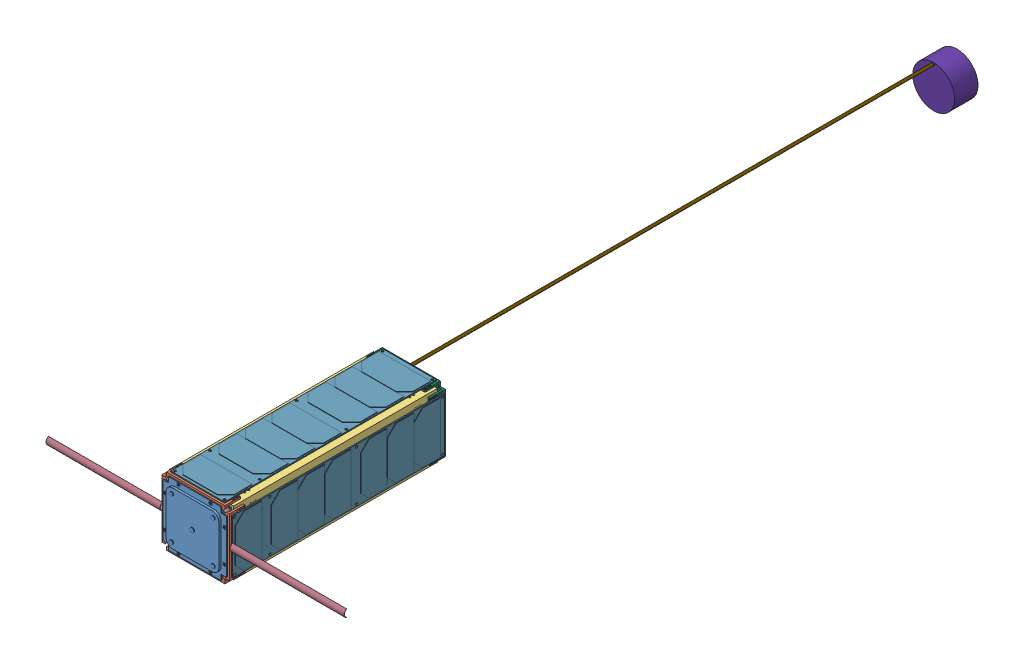
SolidWorks assembly RADIO Unstowed, configuration Default. Lengths in mm.
Overall size (457.2 117.23 1173).
77 component instances, 18 part files, 145 mates.
Components (placement in the parent):
- Nanocom Antenna-1: Nanocom Antenna [Default] at (54.7327 27.087 80.9297) size (98 98 11)
- Top Sipport-1: Top Sipport [Default] at (83.9034 50.4516 80.9297) x (0 -1 0) z (0 0 -1) size (89.4 11 24)
- Top Sipport-2: Top Sipport [Default] at (-15.8818 37.5538 80.9297) x (0 1 0) z (0 0 -1) size (89.4 11 24)
- Top Sipport-3: Top Sipport [Default] at (27.5619 93.8953 80.9297) x (1 0 0) z (0 0 -1) size (89.4 11 24)
- Top Sipport-4: Top Sipport [Default] at (40.4598 -5.8899 80.9297) x (-1 0 0) z (0 0 -1) size (89.4 11 24)
- Support-1: Support [Default] at (-14.9892 90.3455 -221.7132) x (0 -1 0) z (1 0 0) size (18 313 15)
- Support-2: Support [Default] at (-12.332 -4.9973 -221.7132) x (1 0 0) z (0 1 0) size (18 313 15)
- Support-3: Support [Default] at (80.3537 93.0027 -221.7132) x (-1 0 0) z (0 -1 0) size (18 313 15)
- Support-4: Support [Default] at (83.0108 -2.3402 -221.7132) x (0 1 0) z (-1 0 0) size (18 313 15)
- Top Plate2-1: Top Plate2 [Default] at (13.317 21.6849 56.9297) x (-1 0 0) z (0 0 -1) size (92 92 23)
- Nut-1: Nut [Default] at (-1.4892 79.5027 56.9297) size (11.55 10 5.32)
- Nut-2: Nut [Default] at (69.5108 8.5027 56.9297) x (0.821931 0.569587 0) z (0 0 1) size (11.55 10 5.32)
- Nut-3: Nut [Default] at (69.5108 79.5027 56.9297) size (11.55 10 5.32)
- Nut-4: Nut [Default] at (-1.4892 8.5027 56.9297) size (11.55 10 5.32)
- Threaded Rod2-1: Threaded Rod2 [Default] at (69.5108 8.5027 -231.0703) size (6.4 7.01 294.26)
- Threaded Rod2-2: Threaded Rod2 [Default] at (-1.4892 8.5027 -231.0703) size (6.4 7.01 294.26)
- Threaded Rod2-3: Threaded Rod2 [Default] at (-1.4892 79.5027 -231.0703) size (6.4 7.01 294.26)
- Threaded Rod2-4: Threaded Rod2 [Default] at (69.5108 79.5027 -231.0703) size (6.4 7.01 294.26)
- Mid Plate-1: Mid Plate [Default] at (4.649 54.0261 25.9297) size (86 86 3)
- Nut-5: Nut [Default] at (-1.4892 8.5027 20.9297) x (0.999286 -0.037791 0) z (0 0 1) size (11.55 10 5.32)
- Nut-6: Nut [Default] at (-1.4892 8.5027 28.9297) size (11.55 10 5.32)
- Nut-7: Nut [Default] at (69.5108 8.5027 28.9297) size (11.55 10 5.32)
- Nut-8: Nut [Default] at (69.5108 8.5027 20.9297) x (0.921379 0.388666 0) z (0 0 1) size (11.55 10 5.32)
- Nut-9: Nut [Default] at (69.5108 79.5027 28.9297) size (11.55 10 5.32)
- Nut-10: Nut [Default] at (-1.4892 79.5027 28.9297) size (11.55 10 5.32)
- Nut-11: Nut [Default] at (69.5108 79.5027 20.9297) x (0.963517 0.267648 0) z (0 0 1) size (11.55 10 5.32)
- Nut-12: Nut [Default] at (-1.4892 79.5027 20.9297) x (0.997929 0.06432 0) z (0 0 1) size (11.55 10 5.32)
- SDR-1: SDR [Default] at (37.1692 34.198 30.9297) size (65 40 16.8)
- TTC Radio-1: TTC Radio [Default] at (48.3672 78.5027 28.9297) x (0 1 0) z (0 0 1) size (19.7 16 5)
- Raspberry Pi-1: Raspberry Pi [Default] at (63.5108 49.6464 -55.0703) size (66 30.48 5)
- TTC Circuit-1: TTC Circuit [Default] at (24.4431 25.9578 10.9297) size (80 50 10)
- Battery-1: Battery [Default] at (21.7415 31.358 -37.0703) size (70.1 42.59 38.1)
- Tape Antenna-3: Tape Antenna [Default] at (-194.5892 44.2096 75.6458) x (0 -0.999378 0.035253) z (1 0 0) size (11.67 4.21 175)
- Tape Antenna-4: Tape Antenna [Default] at (262.6108 43.4652 75.6178) x (0 0.999544 0.030207) z (-1 0 0) size (11.67 4.21 175)
- Mid Plate-2: Mid Plate [Default] at (4.649 54.0261 7.9297) size (86 86 3)
- Nut-13: Nut [Default] at (-1.4892 8.5027 10.9297) size (11.55 10 5.32)
- Nut-14: Nut [Default] at (69.5108 79.5027 10.9297) size (11.55 10 5.32)
- Nut-15: Nut [Default] at (-1.4892 8.5027 2.9297) size (11.55 10 5.32)
- Nut-16: Nut [Default] at (-1.4892 79.5027 10.9297) size (11.55 10 5.32)
- Nut-17: Nut [Default] at (-1.4892 79.5027 2.9297) size (11.55 10 5.32)
- Nut-18: Nut [Default] at (69.5108 8.5027 2.9297) size (11.55 10 5.32)
- Nut-19: Nut [Default] at (69.5108 8.5027 10.9297) size (11.55 10 5.32)
- Nut-20: Nut [Default] at (69.5108 79.5027 2.9297) size (11.55 10 5.32)
- Mid Plate-3: Mid Plate [Default] at (4.649 54.0261 -40.0703) size (86 86 3)
- Nut-21: Nut [Default] at (69.5108 79.5027 -37.0703) size (11.55 10 5.32)
- Nut-22: Nut [Default] at (-1.4892 8.5027 -40.0703) x (-0.923728 -0.383049 0) z (0 0 -1) size (11.55 10 5.32)
- Nut-23: Nut [Default] at (-1.4892 79.5027 -40.0703) x (-0.923728 -0.383049 0) z (0 0 -1) size (11.55 10 5.32)
- Nut-24: Nut [Default] at (69.5108 8.5027 -37.0703) size (11.55 10 5.32)
- Nut-25: Nut [Default] at (69.5108 79.5027 -40.0703) x (-0.923728 -0.383049 0) z (0 0 -1) size (11.55 10 5.32)
- Nut-26: Nut [Default] at (69.5108 8.5027 -40.0703) x (-0.923728 -0.383049 0) z (0 0 -1) size (11.55 10 5.32)
- Nut-27: Nut [Default] at (-1.4892 8.5027 -37.0703) size (11.55 10 5.32)
- Nut-28: Nut [Default] at (-1.4892 79.5027 -37.0703) size (11.55 10 5.32)
- Nut-29: Nut [Default] at (-1.4892 8.5027 -63.0703) size (11.55 10 5.32)
- Nut-30: Nut [Default] at (69.5108 79.5027 -63.0703) size (11.55 10 5.32)
- Nut-31: Nut [Default] at (69.5108 8.5027 -63.0703) size (11.55 10 5.32)
- Nut-32: Nut [Default] at (-1.4892 8.5027 -55.0703) size (11.55 10 5.32)
- Nut-33: Nut [Default] at (-1.4892 79.5027 -55.0703) size (11.55 10 5.32)
- Nut-34: Nut [Default] at (69.5108 8.5027 -55.0703) size (11.55 10 5.32)
- Nut-35: Nut [Default] at (-1.4892 79.5027 -63.0703) size (11.55 10 5.32)
- Nut-36: Nut [Default] at (69.5108 79.5027 -55.0703) size (11.55 10 5.32)
- Mid Plate-4: Mid Plate [Default] at (4.649 54.0261 -58.0703) size (86 86 3)
- Top Plate2-2: Top Plate2 [Default] at (54.7047 21.6849 -226.0703) size (92 92 23)
- Nut-37: Nut [Default] at (69.5108 8.5027 -226.0703) x (-0.923728 -0.383049 0) z (0 0 -1) size (11.55 10 5.32)
- Nut-38: Nut [Default] at (69.5108 79.5027 -226.0703) x (-0.923728 -0.383049 0) z (0 0 -1) size (11.55 10 5.32)
- Nut-39: Nut [Default] at (-1.4892 8.5027 -226.0703) x (-0.923728 -0.383049 0) z (0 0 -1) size (11.55 10 5.32)
- Nut-40: Nut [Default] at (-1.4892 79.5027 -226.0703) x (-0.923728 -0.383049 0) z (0 0 -1) size (11.55 10 5.32)
- 3U Panel-1: 3U Panel [Default] at (-17.9892 -8.6653 1.9441) x (0 -1 0) z (-1 0 0) size (82.6 325 2.3)
- 3U Panel-5: 3U Panel [Default] at (86.6788 -7.9973 1.9441) x (1 0 0) z (0 -1 0) size (82.6 325 2.3)
- 3U Panel-6: 3U Panel [Default] at (86.0108 96.6707 1.9441) x (0 1 0) z (1 0 0) size (82.6 325 2.3)
- 3U Panel-7: 3U Panel [Default] at (-18.6571 96.0027 1.9441) x (-1 0 0) z (0 1 0) size (82.6 325 2.3)
- Top Support Solar Panel-1: Top Support Solar Panel [Default] at (27.5619 -3.8899 -250.0703) size (89.4 13 24)
- Top Support Solar Panel-2: Top Support Solar Panel [Default] at (81.9034 37.5538 -250.0703) x (0 1 0) z (0 0 1) size (89.4 13 24)
- Top Support Solar Panel-3: Top Support Solar Panel [Default] at (40.4598 91.8953 -250.0703) x (-1 0 0) z (0 0 1) size (89.4 13 24)
- Top Support Solar Panel-4: Top Support Solar Panel [Default] at (-13.8818 50.4516 -250.0703) x (0 -1 0) z (0 0 1) size (89.4 13 24)
- 1U Panel-1: 1U Panel [Default] at (10.1282 49.1305 -250.0703) x (-1 0 0) z (0 0 -1) size (98 98 2.3)
- Mass-1: Mass [Default] at (35.0433 65.173 -1086.0703) x (-0.924883 -0.380251 0) z (0 0 1) size (64 64 36)
- Deployed Boom-1: Deployed Boom [Default] at (35.2379 68.8164 -1050.0703) x (0 0 1) z (-0.999908 -0.013572 0) size (800 1.49 5.53)
Mates (geometry in assembly coordinates):
- Coincident1: coincident: circle of Nanocom Antenna-1; circle of Top Sipport-4
- Coincident2: coincident: circle of Nanocom Antenna-1; circle of Top Sipport-4
- Coincident3: coincident: circle of Nanocom Antenna-1; circle of Top Sipport-2
- Coincident4: coincident: circle of Nanocom Antenna-1; circle of Top Sipport-2
- Coincident5: coincident: circle of Nanocom Antenna-1; circle of Top Sipport-3
- Coincident6: coincident: circle of Nanocom Antenna-1; circle of Top Sipport-3
- Coincident7: coincident: circle of Nanocom Antenna-1; circle of Top Sipport-1
- Coincident8: coincident: circle of Nanocom Antenna-1; circle of Top Sipport-1
- Coincident9: coincident: circle of Top Sipport-2; circle of Support-1
- Coincident10: coincident: circle of Top Sipport-3; circle of Support-1
- Coincident11: coincident: circle of Top Sipport-3; circle of Support-3
- Coincident12: coincident: circle of Top Sipport-1; circle of Support-3
- Coincident13: coincident: circle of Top Sipport-2; circle of Support-2
- Coincident14: coincident: circle of Top Sipport-4; circle of Support-2
- Coincident16: coincident: circle of Top Sipport-4; circle of Support-4
- Coincident17: coincident: circle of Top Sipport-1; circle of Support-4
- Coincident20: coincident: circle of Support-1; circle of Top Plate2-1
- Coincident21: coincident: circle of Support-2; circle of Top Plate2-1
- Coincident22: coincident: circle of Top Plate2-1; circle of Nut-3
- Coincident23: coincident: circle of Top Plate2-1; circle of Nut-1
- Coincident24: coincident: circle of Top Plate2-1; circle of Nut-4
- Coincident25: coincident: circle of Top Plate2-1; circle of Nut-2
- Concentric1: concentric: circle of Top Plate2-1; circle of Threaded Rod2-1
- Coincident26: coincident: plane of Nut-2 through (69.5108 8.5027 61.9297) normal (0 0 1); plane of Threaded Rod2-1 through (69.5108 8.5027 61.9297) normal (0 0 1)
- Concentric2: concentric: circle of Top Plate2-1; circle of Threaded Rod2-4
- Coincident27: coincident: plane of Nut-3 through (69.5108 79.5027 61.9297) normal (0 0 1); plane of Threaded Rod2-4 through (69.5108 79.5027 61.9297) normal (0 0 1)
- Concentric3: concentric: circle of Top Plate2-1; circle of Threaded Rod2-2
- Coincident28: coincident: plane of Nut-4 through (-1.4892 8.5027 61.9297) normal (0 0 1); plane of Threaded Rod2-2 through (-1.4892 8.5027 61.9297) normal (0 0 1)
- Concentric4: concentric: circle of Top Plate2-1; circle of Threaded Rod2-3
- Coincident29: coincident: plane of Nut-1 through (-1.4892 79.5027 61.9297) normal (0 0 1); plane of Threaded Rod2-3 through (-1.4892 79.5027 61.9297) normal (0 0 1)
- Concentric5: concentric: circle of Threaded Rod2-4; circle of Mid Plate-1
- Concentric6: concentric: circle of Threaded Rod2-2; circle of Mid Plate-1
- Concentric7: concentric: circle of Threaded Rod2-2; circle of Nut-6
- Coincident30: coincident: plane of Mid Plate-1 through (4.649 54.0261 28.9297) normal (0 0 1); plane of Nut-6 through (-1.4892 8.5027 28.9297) normal (0 0 -1)
- Concentric8: concentric: circle of Threaded Rod2-2; circle of Nut-5
- Coincident31: coincident: plane of Mid Plate-1 through (4.649 54.0261 25.9297) normal (0 0 -1); plane of Nut-5 through (-1.4892 8.5027 25.9297) normal (0 0 1)
- Concentric9: concentric: circle of Threaded Rod2-1; circle of Nut-7
- Coincident32: coincident: plane of Mid Plate-1 through (4.649 54.0261 28.9297) normal (0 0 1); plane of Nut-7 through (69.5108 8.5027 28.9297) normal (0 0 -1)
- Concentric10: concentric: circle of Threaded Rod2-1; circle of Nut-8
- Coincident33: coincident: plane of Mid Plate-1 through (4.649 54.0261 25.9297) normal (0 0 -1); plane of Nut-8 through (69.5108 8.5027 25.9297) normal (0 0 1)
- Concentric11: concentric: circle of Threaded Rod2-4; circle of Nut-9
- Coincident34: coincident: plane of Mid Plate-1 through (4.649 54.0261 28.9297) normal (0 0 1); plane of Nut-9 through (69.5108 79.5027 28.9297) normal (0 0 -1)
- Concentric12: concentric: circle of Threaded Rod2-3; circle of Nut-10
- Coincident35: coincident: plane of Mid Plate-1 through (4.649 54.0261 28.9297) normal (0 0 1); plane of Nut-10 through (-1.4892 79.5027 28.9297) normal (0 0 -1)
- Concentric13: concentric: circle of Threaded Rod2-4; circle of Nut-11
- Coincident36: coincident: plane of Mid Plate-1 through (4.649 54.0261 25.9297) normal (0 0 -1); plane of Nut-11 through (69.5108 79.5027 25.9297) normal (0 0 1)
- Concentric14: concentric: circle of Threaded Rod2-3; circle of Nut-12
- Coincident37: coincident: plane of Mid Plate-1 through (4.649 54.0261 25.9297) normal (0 0 -1); plane of Nut-12 through (-1.4892 79.5027 25.9297) normal (0 0 1)
- Distance1: distance = 25 mm: plane of Mid Plate-1 through (4.649 54.0261 28.9297) normal (0 0 1); plane of Top Plate2-1 through (13.317 21.6849 53.9297) normal (0 0 -1)
- Coincident39: coincident: plane of Mid Plate-1 through (4.649 54.0261 28.9297) normal (0 0 1); plane of SDR-1 through (37.1692 34.198 28.9297) normal (0 0 -1)
- Distance4: distance = 12 mm: line of SDR-1 through (65.0108 16.0027 28.9297) axis (0 1 0); line of Mid Plate-1 through (77.0108 4.0027 28.9297) axis (0 1 0)
- Distance5: distance = 15 mm: line of SDR-1 through (0.0108 16.0027 28.9297) axis (1 0 0); line of Mid Plate-1 through (-5.9892 1.0027 28.9297) axis (1 0 0)
- Coincident46: coincident: plane of Mid Plate-1 through (4.649 54.0261 28.9297) normal (0 0 1); plane of TTC Radio-1 through (48.3672 78.5027 28.9297) normal (0 0 -1)
- Distance8: distance = 20 mm: plane of TTC Radio-1 through (57.0108 78.5027 30.9297) normal (1 0 0); plane of Mid Plate-1 through (77.0108 4.0027 28.9297) normal (1 0 0)
- Distance9: distance = 5 mm: plane of TTC Radio-1 through (48.3672 82.0027 30.9297) normal (0 1 0); line of Mid Plate-1 through (74.0108 87.0027 28.9297) axis (-1 0 0)
- Coincident53: coincident: plane of TTC Circuit-1 through (24.4431 25.9578 10.9297) normal (0 0 -1); plane of Mid Plate-2 through (4.649 54.0261 10.9297) normal (0 0 1)
- Distance10: distance = 5 mm: line of TTC Circuit-1 through (-4.4066 66.0027 12.9297) axis (0 -1 0); line of Mid Plate-2 through (-8.9892 84.0027 10.9297) axis (0 -1 0)
- Distance13: distance = 21.095 mm: line of TTC Circuit-1 through (75.5934 66.0027 12.9297) axis (-1 0 0); line of Mid Plate-2 through (74.0108 87.0027 10.9297) axis (-1 0 0)
- Concentric16: concentric: circle of Threaded Rod2-2; circle of Mid Plate-2
- Concentric18: concentric: circle of Threaded Rod2-4; circle of Mid Plate-2
- Concentric19: concentric: circle of Threaded Rod2-4; circle of Nut-14
- Coincident59: coincident: plane of Mid Plate-2 through (4.649 54.0261 10.9297) normal (0 0 1); plane of Nut-14 through (69.5108 79.5027 10.9297) normal (0 0 -1)
- Concentric20: concentric: circle of Threaded Rod2-4; circle of Nut-20
- Coincident60: coincident: plane of Mid Plate-2 through (4.649 54.0261 7.9297) normal (0 0 -1); plane of Nut-20 through (69.5108 79.5027 7.9297) normal (0 0 1)
- Concentric21: concentric: circle of Threaded Rod2-1; circle of Nut-19
- Coincident61: coincident: plane of Mid Plate-2 through (4.649 54.0261 10.9297) normal (0 0 1); plane of Nut-19 through (69.5108 8.5027 10.9297) normal (0 0 -1)
- Concentric22: concentric: circle of Threaded Rod2-1; circle of Nut-18
- Coincident62: coincident: plane of Mid Plate-2 through (4.649 54.0261 7.9297) normal (0 0 -1); plane of Nut-18 through (69.5108 8.5027 7.9297) normal (0 0 1)
- Concentric23: concentric: circle of Threaded Rod2-2; circle of Nut-13
- Coincident63: coincident: plane of Mid Plate-2 through (4.649 54.0261 10.9297) normal (0 0 1); plane of Nut-13 through (-1.4892 8.5027 10.9297) normal (0 0 -1)
- Concentric24: concentric: circle of Threaded Rod2-2; circle of Nut-15
- Coincident64: coincident: plane of Mid Plate-2 through (4.649 54.0261 7.9297) normal (0 0 -1); plane of Nut-15 through (-1.4892 8.5027 7.9297) normal (0 0 1)
- Concentric25: concentric: circle of Threaded Rod2-3; circle of Nut-16
- Coincident65: coincident: plane of Mid Plate-2 through (4.649 54.0261 10.9297) normal (0 0 1); plane of Nut-16 through (-1.4892 79.5027 10.9297) normal (0 0 -1)
- Concentric26: concentric: circle of Threaded Rod2-3; circle of Nut-17
- Coincident66: coincident: plane of Mid Plate-2 through (4.649 54.0261 7.9297) normal (0 0 -1); plane of Nut-17 through (-1.4892 79.5027 7.9297) normal (0 0 1)
- Distance14: distance = 15 mm: plane of Mid Plate-2 through (4.649 54.0261 10.9297) normal (0 0 1); plane of Mid Plate-1 through (4.649 54.0261 25.9297) normal (0 0 -1)
- Coincident68: coincident: circle of Mid Plate-3; circle of Nut-21
- Coincident69: coincident: circle of Mid Plate-3; circle of Nut-24
- Coincident70: coincident: circle of Mid Plate-3; circle of Nut-27
- Coincident71: coincident: circle of Mid Plate-3; circle of Nut-28
- Coincident72: coincident: circle of Mid Plate-3; circle of Nut-25
- Coincident73: coincident: circle of Mid Plate-3; circle of Nut-23
- Coincident74: coincident: circle of Mid Plate-3; circle of Nut-22
- Coincident76: coincident: circle of Mid Plate-3; circle of Nut-26
- Coincident77: coincident: plane of Battery-1 through (21.7415 31.358 -37.0703) normal (0 0 -1); plane of Mid Plate-3 through (4.649 54.0261 -37.0703) normal (0 0 1)
- Distance16: distance = 30 mm: line of Battery-1 through (57.8687 57.4223 -32.0703) axis (-1 0 0); line of Mid Plate-3 through (74.0108 87.0027 -37.0703) axis (-1 0 0)
- Distance17: distance = 15 mm: line of Battery-1 through (62.8687 24.8323 -32.0703) axis (0 1 0); line of Mid Plate-3 through (77.0108 4.0027 -37.0703) axis (0 1 0)
- Concentric27: concentric: circle of Threaded Rod2-2; circle of Nut-27
- Concentric28: concentric: circle of Threaded Rod2-4; circle of Nut-21
- Distance18: distance = 45 mm: plane of Mid Plate-3 through (4.649 54.0261 -37.0703) normal (0 0 1); plane of Mid Plate-2 through (4.649 54.0261 7.9297) normal (0 0 -1)
- Coincident83: coincident: plane of Raspberry Pi-1 through (63.5108 49.6464 -55.0703) normal (0 0 -1); plane of Mid Plate-4 through (4.649 54.0261 -55.0703) normal (0 0 1)
- Distance19: distance = 30 mm: line of Raspberry Pi-1 through (67.0108 57.0027 -55.0703) axis (-1 0 0); line of Mid Plate-4 through (74.0108 87.0027 -55.0703) axis (-1 0 0)
- Distance20: distance = 10 mm: line of Raspberry Pi-1 through (67.0108 26.5227 -55.0703) axis (0 1 0); line of Mid Plate-4 through (77.0108 4.0027 -55.0703) axis (0 1 0)
- Concentric29: concentric: circle of Nut-29; circle of Mid Plate-4
- Coincident87: coincident: plane of Nut-29 through (-1.4892 8.5027 -58.0703) normal (0 0 1); plane of Mid Plate-4 through (4.649 54.0261 -58.0703) normal (0 0 -1)
- Concentric30: concentric: circle of Nut-31; circle of Mid Plate-4
- Coincident89: coincident: plane of Nut-31 through (69.5108 8.5027 -58.0703) normal (0 0 1); plane of Mid Plate-4 through (4.649 54.0261 -58.0703) normal (0 0 -1)
- Concentric31: concentric: circle of Nut-30; circle of Mid Plate-4
- Coincident91: coincident: plane of Nut-30 through (69.5108 79.5027 -58.0703) normal (0 0 1); plane of Mid Plate-4 through (4.649 54.0261 -58.0703) normal (0 0 -1)
- Concentric32: concentric: circle of Nut-35; circle of Mid Plate-4
- Coincident93: coincident: plane of Nut-35 through (-1.4892 79.5027 -58.0703) normal (0 0 1); plane of Mid Plate-4 through (4.649 54.0261 -58.0703) normal (0 0 -1)
- Coincident94: coincident: circle of Nut-33; circle of Mid Plate-4
- Coincident95: coincident: circle of Nut-32; circle of Mid Plate-4
- Coincident96: coincident: circle of Nut-36; circle of Mid Plate-4
- Coincident97: coincident: circle of Nut-34; circle of Mid Plate-4
- Concentric33: concentric: circle of Threaded Rod2-2; circle of Nut-29
- Concentric34: concentric: circle of Threaded Rod2-3; circle of Nut-35
- Distance21: distance = 15 mm: plane of Mid Plate-4 through (4.649 54.0261 -55.0703) normal (0 0 1); plane of Mid Plate-3 through (4.649 54.0261 -40.0703) normal (0 0 -1)
- Coincident100: coincident: circle of Top Plate2-2; circle of Nut-37
- Coincident101: coincident: circle of Top Plate2-2; circle of Nut-39
- Coincident102: coincident: circle of Top Plate2-2; circle of Nut-38
- Coincident103: coincident: circle of Top Plate2-2; circle of Nut-40
- Concentric35: concentric: circle of Threaded Rod2-3; circle of Top Plate2-2
- Concentric36: concentric: circle of Threaded Rod2-4; circle of Top Plate2-2
- Coincident104: coincident: plane of Threaded Rod2-4 through (69.5108 79.5027 -231.0703) normal (0 0 -1); plane of Nut-38 through (69.5108 79.5027 -231.0703) normal (0 0 -1)
- Coincident123: coincident: circle of Top Sipport-2; circle of 3U Panel-1
- Coincident124: coincident: circle of Top Sipport-2; circle of 3U Panel-1
- Coincident125: coincident: circle of Top Sipport-4; circle of 3U Panel-5
- Coincident126: coincident: circle of Top Sipport-4; circle of 3U Panel-5
- Coincident127: coincident: circle of Top Sipport-3; circle of 3U Panel-7
- Coincident128: coincident: circle of Top Sipport-3; circle of 3U Panel-7
- Coincident129: coincident: circle of Top Sipport-1; circle of 3U Panel-6
- Coincident130: coincident: circle of Top Sipport-1; circle of 3U Panel-6
- Coincident131: coincident: point of Tape Antenna-4; line of 3U Panel-6 through (87.6108 85.3027 77.9297) axis (0 -1 0)
- Coincident132: coincident: point of Tape Antenna-4; line of 3U Panel-6 through (87.6108 85.3027 77.9297) axis (0 -1 0)
- Coincident137: coincident: point of Tape Antenna-3; line of 3U Panel-1 through (-19.5892 2.7027 77.9297) axis (0 1 0)
- Coincident138: coincident: point of Tape Antenna-3; line of 3U Panel-1 through (-19.5892 2.7027 77.9297) axis (0 1 0)
- Coincident140: coincident: circle of 3U Panel-6; circle of Top Support Solar Panel-2
- Coincident141: coincident: circle of 3U Panel-6; circle of Top Support Solar Panel-2
- Coincident142: coincident: circle of 3U Panel-5; circle of Top Support Solar Panel-1
- Coincident143: coincident: circle of 3U Panel-5; circle of Top Support Solar Panel-1
- Coincident144: coincident: circle of 3U Panel-1; circle of Top Support Solar Panel-4
- Coincident145: coincident: circle of 3U Panel-1; circle of Top Support Solar Panel-4
- Coincident146: coincident: circle of 3U Panel-7; circle of Top Support Solar Panel-3
- Coincident147: coincident: circle of 3U Panel-7; circle of Top Support Solar Panel-3
- Coincident148: coincident: circle of Top Support Solar Panel-3; circle of 1U Panel-1
- Coincident149: coincident: circle of Top Support Solar Panel-1; circle of 1U Panel-1
- Parallel21: parallel: line of Nanocom Antenna-1 through (74.5108 93.0027 82.4297) axis (-1 0 0); line of Tape Antenna-3 through (-19.5892 50.0375 78.0383) axis (-1 0 0)
- Parallel22: parallel: line of Nanocom Antenna-1 through (74.5108 93.0027 82.4297) axis (-1 0 0); line of Tape Antenna-4 through (87.6108 49.3257 77.9297) axis (1 0 0)
- Parallel23: parallel: line of Support-1 through (-14.9892 93.0027 -241.0703) axis (0 0 1); line of Deployed Boom-1 through (37.3663 96.0027 -250.0703) axis (0 0 -1)
- Coincident157: coincident: line of Top Support Solar Panel-3 through (78.7108 96.0027 -250.0703) axis (-1 0 0); point of Deployed Boom-1
- Coincident158: coincident: line of Top Support Solar Panel-3 through (78.7108 96.0027 -250.0703) axis (-1 0 0); point of Deployed Boom-1
- Distance25: distance = 43 mm: point of Deployed Boom-1; point of Top Support Solar Panel-3
- Coincident160: coincident: plane of Mass-1 through (35.0433 65.173 -1050.0703) normal (0 0 1); plane of Deployed Boom-1 through (34.8386 98.2368 -1050.0703) normal (0 0 -1)
